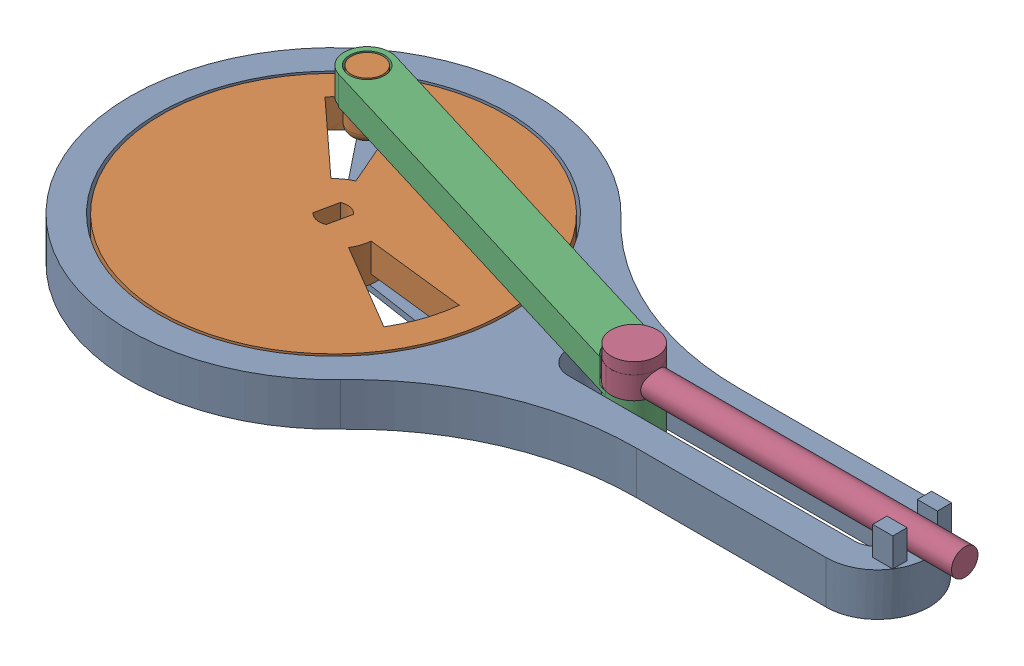
SolidWorks assembly MotorActuatorAssembly_v1.000.001, configuration Default. Lengths in mm.
Overall size (152.1 14.18 84).
4 component instances, 4 part files, 7 mates.
Components (placement in the parent):
- Chassis_v1.000.001-1: Chassis_v1.000.001 [Default] at origin size (139.5 12.5 71)
- Cog_v1.000.001-1: Cog_v1.000.001 [Default] at (-39.1882 0 32.0018) x (0.599956 0 -0.800033) z (0.800033 0 0.599956) size (60 11.56 60)
- Linkage_v1.000.001-1: Linkage_v1.000.001 [Default] at (-23.6931 0 4.518) x (0.998659 0 -0.051772) z (0.051772 0 0.998659) size (73.85 12.5 31.81)
- Presser_v1.000.001-1: Presser_v1.000.001 [Default] at (-20.9521 -0.2 -0.0003) size (61.63 6.7 8.04)
Mates (geometry in assembly coordinates):
- Coincident2: coincident anti-aligned: plane of Chassis_v1.000.001-1 through (12.4055 45.1742 55.1864) normal (0 1 0); plane of Cog_v1.000.001-1 through (12.4055 45.1742 55.1864) normal (0 -1 0)
- Concentric1: concentric aligned: cylinder of Cog_v1.000.001-1 through (-2.0819 56.8891 34.8121) axis (0 1 0) radius 2.75; cylinder of Linkage_v1.000.001-1 through (-2.0819 56.8891 34.8121) axis (0 1 0) radius 3.0628
- Concentric2: concentric aligned: cylinder of Linkage_v1.000.001-1 through (64.8935 56.3914 55.1661) axis (0 -1 0) radius 3.4622; cylinder of Presser_v1.000.001-1 through (64.8935 56.0711 55.1661) axis (0 -1 0) radius 3.4622
- Coincident3: coincident anti-aligned: plane of Linkage_v1.000.001-1 through (72.9688 52.4499 28.6231) normal (0 1 0); plane of Presser_v1.000.001-1 through (72.192 52.4499 28.3991) normal (0 -1 0)
- Tangent3: tangent anti-aligned: plane of Chassis_v1.000.001-1 through (12.4055 51.6742 51.1864) normal (0 0 1); cylinder of Linkage_v1.000.001-1 through (64.8874 56.6742 55.1864) axis (0 -1 0) radius 4
- Concentric3: concentric aligned: cylinder of Chassis_v1.000.001-1 through (12.4055 46.6742 55.1864) axis (0 -1 0) radius 5; circle of Cog_v1.000.001-1
- Concentric4: concentric anti-aligned: cylinder of Chassis_v1.000.001-1 through (12.4055 51.6742 55.1864) axis (0 -1 0) radius 30.5; cylinder of Cog_v1.000.001-1 through (12.4055 46.6742 55.1864) axis (0 1 0) radius 30
